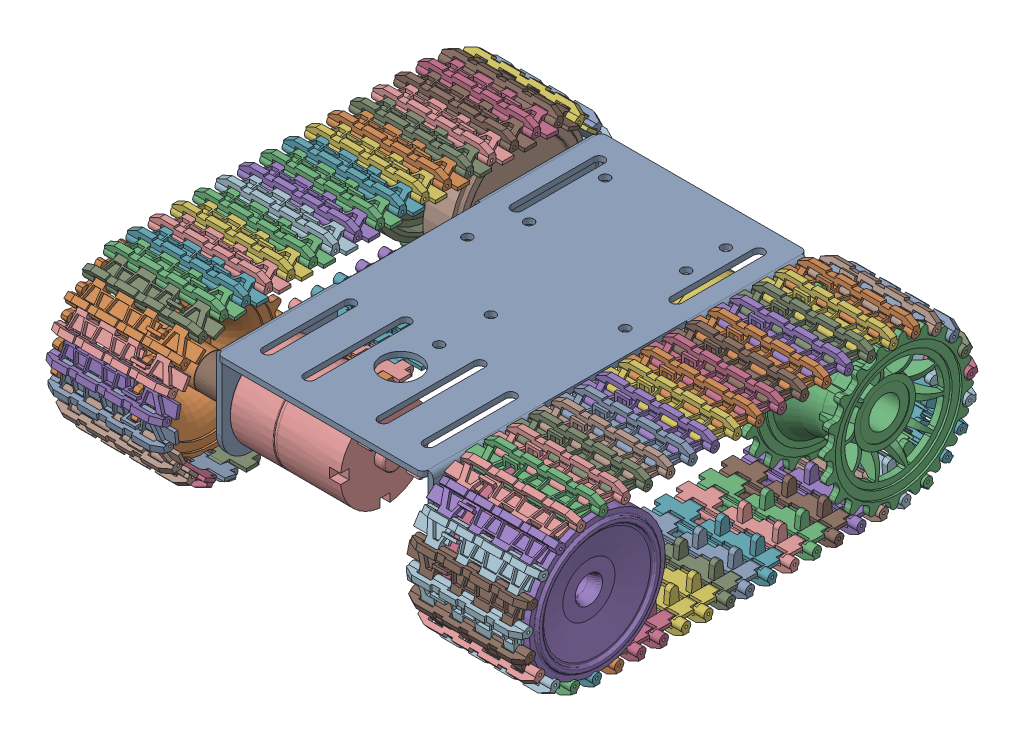
SolidWorks assembly Mini TP101 Smart Tank Chassis, configuration Default. Lengths in mm.
Overall size (173.8 71.3 180.56).
13 component instances, 7 part files, 0 mates.
Components (placement in the parent):
- Base Frame-1: Base Frame [Default] at (60.6644 78.7904 111.7014) size (79 37 140)
- DriverWheel-1: DriverWheel [Default] at (-9.5356 57.0404 166.6012) x (1 0 0) z (0 0.924225 0.381849) size (31.4 54.59 54.59)
- DriverWheel-2: DriverWheel [Default] at (130.8644 57.0404 56.8017) x (-1 0 0) z (0 -0.057411 -0.998351) size (31.4 54.59 54.59)
- FreeWheel_a-1: FreeWheel_a [Default] at (113.4144 57.1904 166.6014) x (0 0.96658 -0.256365) z (0 0.256365 0.96658) size (49.65 25.15 49.65)
- FreeWheel_b-1: FreeWheel_b [Default] at (120.0644 57.1904 166.6014) x (0 1 0) z (0 0 1) size (49.6 27.5 49.6)
- HTE-33GB-520-18.7 Motor-1: HTE-33GB-520-18.7 Motor [Default] at (82.1644 57.0103 62.8016) x (0 -0.999987 -0.005025) z (-1 0 0) size (32.75 32.75 56.05)
- Motor Horn-1: Motor Horn [Default] at (100.6644 57.0404 56.8017) x (1 0 0) z (0 0.057411 0.998351) size (23.01 11.9 11.9)
- FreeWheel_a-2: FreeWheel_a [Default] at (7.9144 57.1904 56.8014) x (0 -0.703844 0.710354) z (0 0.710354 0.703844) size (49.65 25.15 49.65)
- FreeWheel_b-2: FreeWheel_b [Default] at (1.2644 57.1904 56.8014) x (0 -0.876069 -0.482185) z (0 -0.482185 0.876069) size (49.6 27.5 49.6)
- HTE-33GB-520-18.7 Motor-2: HTE-33GB-520-18.7 Motor [Default] at (39.1644 57.0103 160.6013) x (0 -0.999987 0.005025) z (1 0 0) size (32.75 32.75 56.05)
- Motor Horn-2: Motor Horn [Default] at (20.6644 57.0404 166.6012) x (-1 0 0) z (0 -0.924225 -0.381849) size (23.01 11.9 11.9)
- SinglePart Crawler-1: SinglePart Crawler [Default] at (125.1144 31.4354 111.7366) x (1 0 0) z (0 0.001366 0.999999) size (44.5 59.42 169.22)
- SinglePart Crawler-2: SinglePart Crawler [Default] at (-3.7856 31.4354 111.6663) x (-1 0 0) z (0 0.001366 -0.999999) size (44.5 59.42 169.22)
